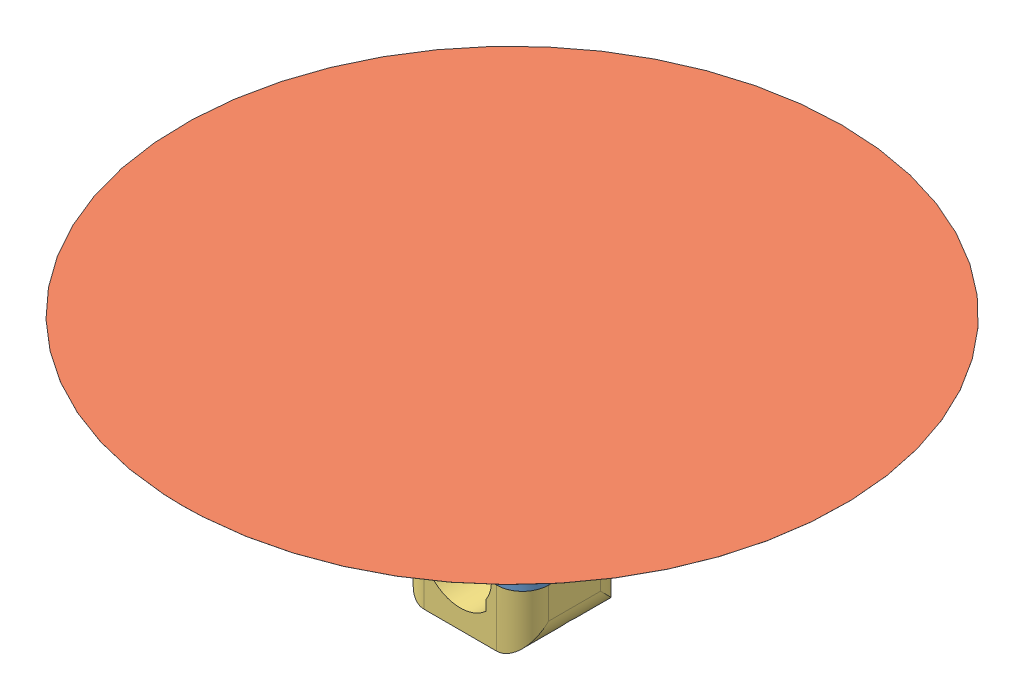
SolidWorks assembly Assem6, configuration Default. Lengths in mm.
Overall size (127 47.51 127).
3 component instances, 3 part files, 5 mates.
Components (placement in the parent):
- heewing5c-1: heewing5c [Default] at origin size (24 20.48 20.25)
- motor-1: motor [Default] at (0 4 0) size (127 16.51 127)
- heewing5d-1: heewing5d [Default] at (0 -16 0) size (24 11 20)
Mates (geometry in assembly coordinates):
- Coincident2: coincident anti-aligned: plane of heewing5c-1 through (0 -16 10) normal (0 -1 0); plane of heewing5d-1 through (0 -16 10) normal (0 1 0)
- Concentric3: concentric aligned: cylinder of heewing5c-1 through (8.5 -16 0) axis (0 1 0) radius 1.9; cylinder of heewing5d-1 through (8.5 -33 0) axis (0 1 0) radius 1.25
- Concentric4: concentric aligned: cylinder of heewing5c-1 through (-8.5 -16 0) axis (0 1 0) radius 1.9; cylinder of heewing5d-1 through (-8.5 -33 0) axis (0 1 0) radius 1.25
- Concentric6: concentric aligned: cylinder of heewing5c-1 through (0 10 0) axis (0 -1 0) radius 2.25; cylinder of motor-1 through (0 19.5 0) axis (0 -1 0) radius 10.65
- Coincident3: coincident anti-aligned: plane of heewing5c-1 through (0 4 0) normal (0 1 0); plane of motor-1 through (0 4 0) normal (0 -1 0)
